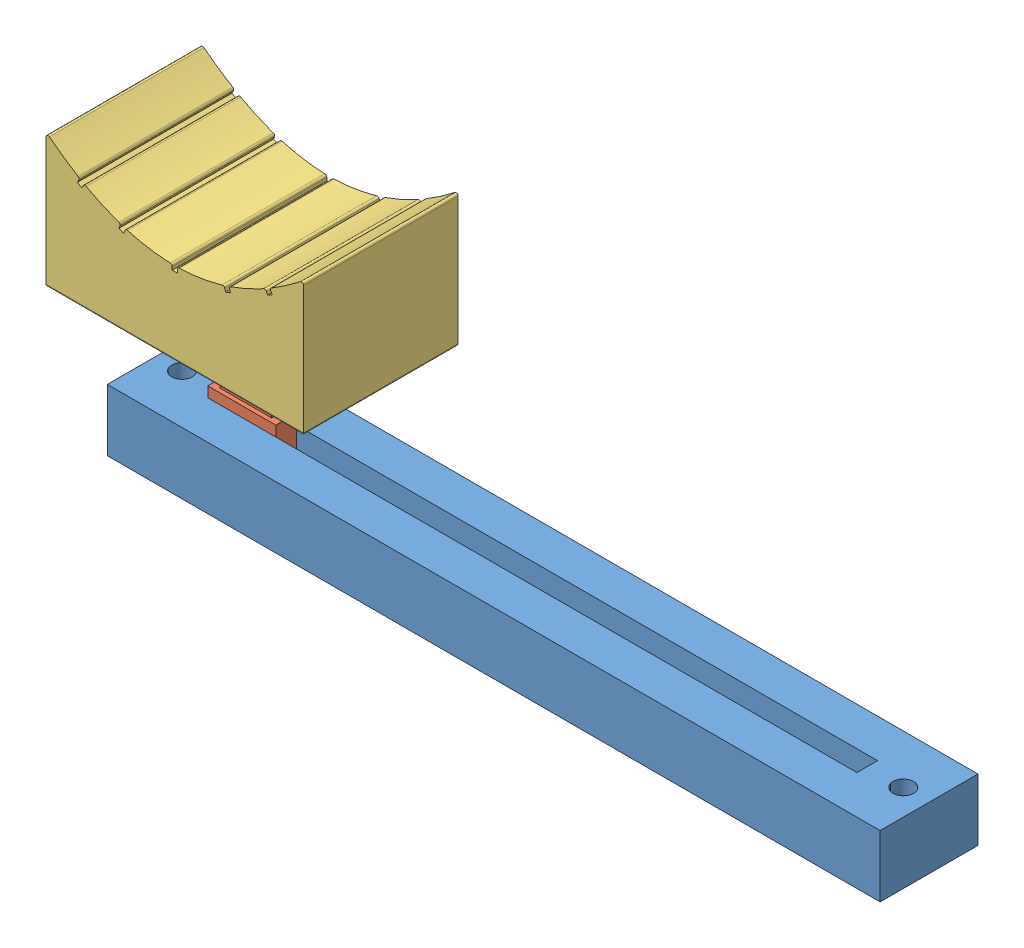
SolidWorks assembly Montagem pot, configuration Default. Lengths in mm.
Overall size (78.2 26.79 15).
3 component instances, 3 part files, 6 mates.
Components (placement in the parent):
- Part1-1: Part1 [Default] at (-89.0124 11.2751 22.2341) size (75 6 9.5)
- Pino do pot-1: Pino do pot [Default] at (-79.7124 14.2751 17.4841) size (6.6 18 2)
- Camisinha do pino-1: Camisinha do pino [Default] at (-67.2124 25.2751 24.9841) x (0 0 -1) z (1 0 0) size (15 12.79 25)
Mates (geometry in assembly coordinates):
- Coincident1: coincident anti-aligned: plane of Part1-1 through (-83.0124 14.2751 18.4841) normal (0 0 -1); plane of Pino do pot-1 through (-83.0124 18.2751 18.4841) normal (0 0 1)
- Coincident2: coincident anti-aligned: plane of Part1-1 through (-89.0124 14.2751 22.2341) normal (0 1 0); plane of Pino do pot-1 through (-79.7124 14.2751 17.4841) normal (0 -1 0)
- Coincident3: coincident anti-aligned: plane of Pino do pot-1 through (-82.2124 22.2751 18.0841) normal (0 0 1); plane of Camisinha do pino-1 through (-81.7124 32.2751 18.0841) normal (0 0 -1)
- Coincident4: coincident anti-aligned: plane of Pino do pot-1 through (-77.7124 32.2751 18.0841) normal (1 0 0); plane of Camisinha do pino-1 through (-77.7124 32.2751 18.0841) normal (-1 0 0)
- Coincident5: coincident anti-aligned: plane of Pino do pot-1 through (-79.7124 32.2751 17.4841) normal (0 1 0); plane of Camisinha do pino-1 through (-67.2124 32.2751 24.9841) normal (0 -1 0)
- LimitDistance1: limit distance = 0 mm anti-aligned: plane of Part1-1 through (-83.0124 14.2751 16.4841) normal (1 0 0); plane of Pino do pot-1 through (-83.0124 18.2751 18.4841) normal (-1 0 0)
